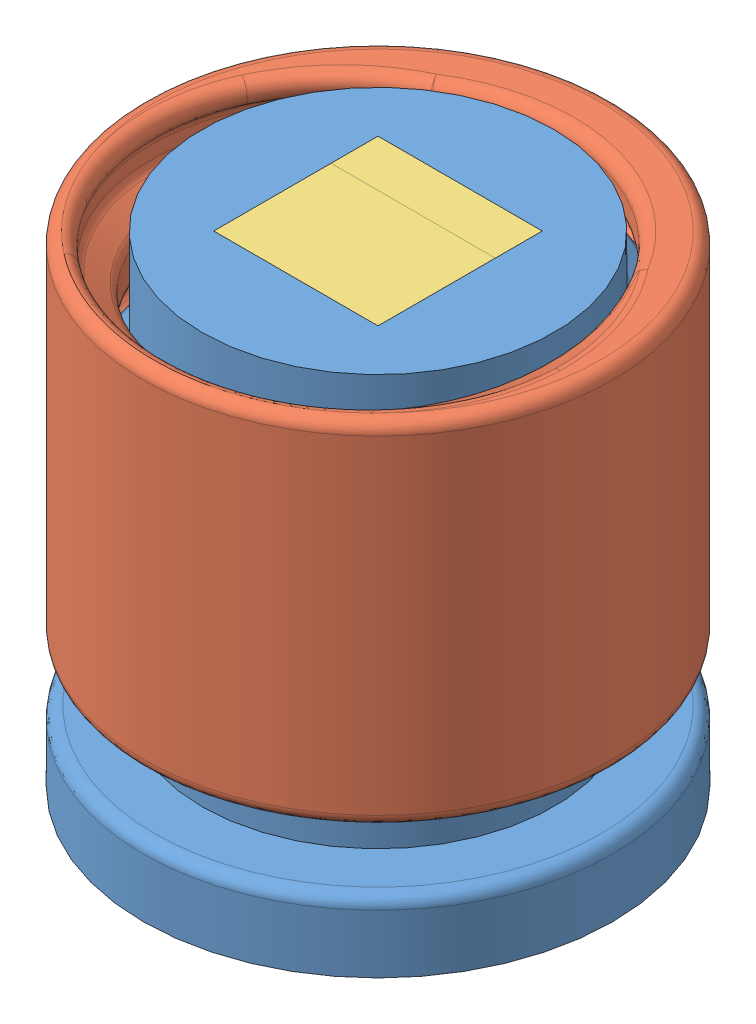
SolidWorks assembly bulkhead assembly small, configuration Default. Lengths in mm.
Overall size (28.26 26.72 28.3).
4 component instances, 3 part files, 9 mates.
Components (placement in the parent):
- bulkhead body small-1: bulkhead body small [Default] at (13.2212 6.6024 19.6303) size (25.4 26.04 25.4)
- bulkhead nut small-1: bulkhead nut small [Default] at (13.2212 9.7774 19.6303) x (0.992841 0 0.119441) z (-0.119441 0 0.992841) size (25.4 20.41 25.45)
- 93565K118_Super-Cushioning Polyethylene Foam Strip-1: 93565K118_Super-Cushioning Polyethylene Foam Strip [93565K118] at (13.2212 15.1749 18.0428) x (0 0 -1) z (0 -1 0) size (9.53 12.7 24.77)
- 93565K118_Super-Cushioning Polyethylene Foam Strip-2: 93565K118_Super-Cushioning Polyethylene Foam Strip [93565K118] at (13.2212 15.1749 21.2178) x (0 0 -1) z (0 1 0) size (9.53 12.7 24.77)
Mates (geometry in assembly coordinates):
- Concentric1: concentric anti-aligned: cylinder of bulkhead body small-1 through (13.2212 2.7924 19.6303) axis (0 1 0) radius 12.7; cylinder of bulkhead nut small-1 through (13.2212 28.8274 19.6303) axis (0 -1 0) radius 12.7
- Screw1: screw = 1 anti-aligned: cylinder of bulkhead body small-1 through (13.2212 2.7924 19.6303) axis (0 1 0) radius 12.7; cylinder of bulkhead nut small-1 through (13.2212 28.8274 19.6303) axis (0 -1 0) radius 12.7
- LimitDistance1: limit distance = 3.175 mm anti-aligned: plane of bulkhead nut small-1 through (13.2212 9.7774 19.6303) normal (0 -1 0); plane of bulkhead body small-1 through (13.2212 6.6024 19.6303) normal (0 1 0)
- Coincident1: coincident anti-aligned: plane of bulkhead body small-1 through (6.8712 28.8274 13.2803) normal (0 0 1); plane of 93565K118_Super-Cushioning Polyethylene Foam Strip-1 through (19.5712 2.7924 13.2803) normal (0 0 -1)
- Coincident2: coincident anti-aligned: plane of bulkhead body small-1 through (6.8712 28.8274 13.2803) normal (1 0 0); plane of 93565K118_Super-Cushioning Polyethylene Foam Strip-1 through (6.8712 2.7924 22.8053) normal (-1 0 0)
- Coincident3: coincident aligned: plane of bulkhead body small-1 through (13.2212 2.7924 19.6303) normal (0 -1 0); plane of 93565K118_Super-Cushioning Polyethylene Foam Strip-1 through (13.2212 2.7924 18.0428) normal (0 -1 0)
- Coincident4: coincident anti-aligned: plane of bulkhead body small-1 through (6.8712 28.8274 25.9803) normal (0 0 -1); plane of 93565K118_Super-Cushioning Polyethylene Foam Strip-2 through (6.8712 27.5574 25.9803) normal (0 0 1)
- Coincident5: coincident anti-aligned: plane of bulkhead body small-1 through (19.5712 28.8274 13.2803) normal (-1 0 0); plane of 93565K118_Super-Cushioning Polyethylene Foam Strip-2 through (19.5712 27.5574 25.9803) normal (1 0 0)
- Coincident6: coincident aligned: plane of bulkhead body small-1 through (13.2212 2.7924 19.6303) normal (0 -1 0); plane of 93565K118_Super-Cushioning Polyethylene Foam Strip-2 through (13.2212 2.7924 21.2178) normal (0 -1 0)
